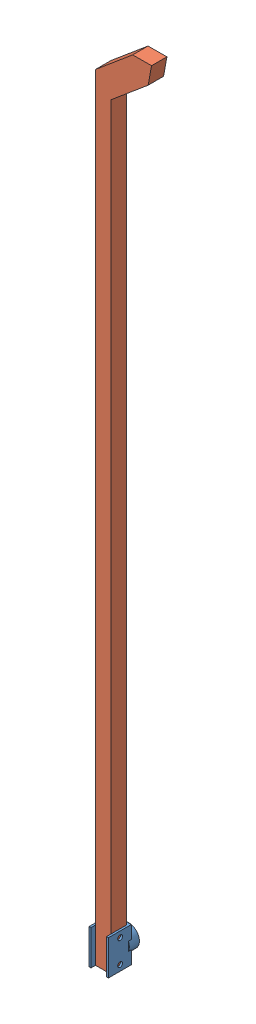
SolidWorks assembly Sensor Arm, configuration Default. Lengths in mm.
Overall size (22 800 30.91).
2 component instances, 2 part files, 4 mates.
Components (placement in the parent):
- ProfilHub-1: ProfilHub [Default] at (-21.0152 -37.6359 -25.453) size (22 36 30.91)
- ProfileSensor^Sensor Arm-1: ProfileSensor^Sensor Arm [Default] at (-21.0152 -37.6359 -15.053) size (16 800 15.88) (virtual)
Mates (geometry in assembly coordinates):
- InPlace1: in place: plane of ProfilHub-1 through (9.4848 7.3641 -15.053) normal (0 0 1); plane of ? through (0 0 -15.053) normal (0 0 1); moOrthogonalPlaneRef_w of ProfilHub-1 through (9.4848 7.3641 -15.053) normal (0 0 1); plane of ? through (0 0 -15.053) normal (0 1 0); plane of ProfilHub-1 through (9.4848 7.3641 -15.053) normal (0 0 1); plane of ? through (0 0 -15.053) normal (1 0 0); plane of ProfilHub-1 through (9.4848 7.3641 -15.053) normal (0 0 1); unknown of ProfileSensor^Sensor Arm-1
- Coincident1: coincident aligned: plane of ?; plane of ?
- Coincident2: coincident aligned: moOrthogonalPlaneRef_w of ProfilHub-1 through (-21.0152 -37.6359 -15.053) normal (0 1 0); plane of Part17^Assem7-1 through (-21.0152 -37.6359 -15.053) normal (0 1 0)
- Coincident3: coincident anti-aligned: moOrthogonalPlaneRef_w of ProfilHub-1 through (-21.0152 -37.6359 -15.053) normal (-1 0 0); plane of Part17^Assem7-1 through (-21.0152 -37.6359 -15.053) normal (1 0 0)
